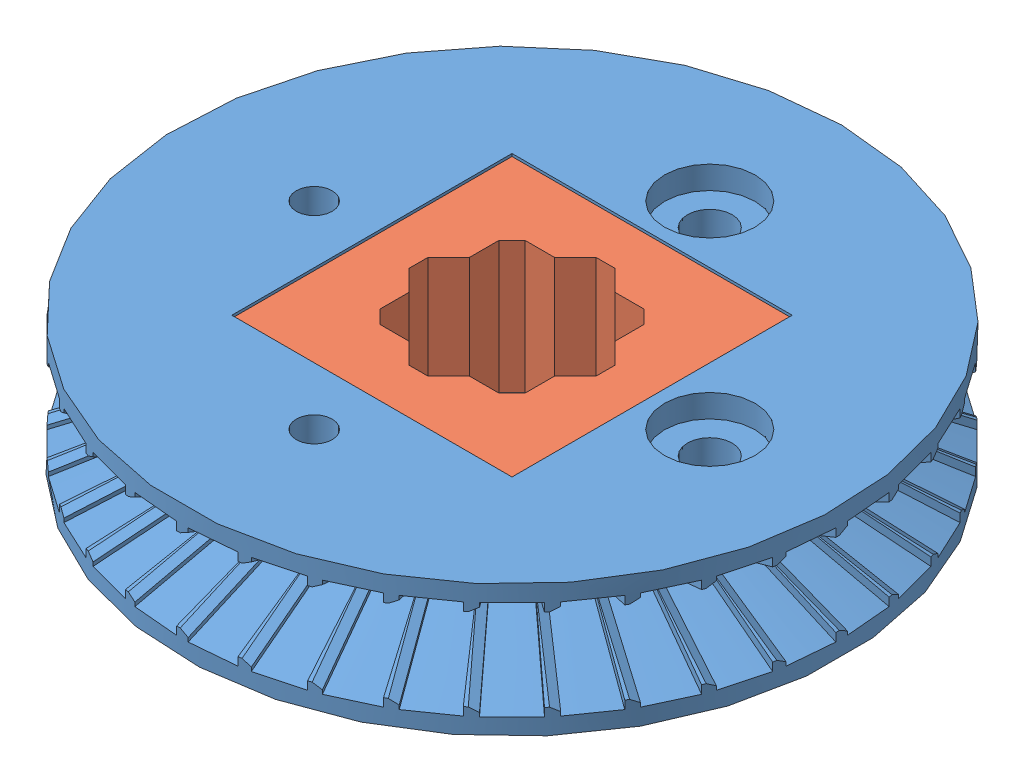
SolidWorks assembly AngledToothWinchDrum, configuration Default. Lengths in mm.
Overall size (63.5 12.7 63.5).
3 component instances, 2 part files, 5 mates.
Components (placement in the parent):
- AngledToothWinchDriver-1: AngledToothWinchDriver [Default] at origin size (63.5 6.35 63.5)
- AngledToothWinchDriver-2: AngledToothWinchDriver [Mirrored] at (0 12.7 0) x (0 0 1) z (1 0 0) size (63.5 6.35 63.5)
- MazdaMotorWinchPlug-1: MazdaMotorWinchPlug [Default] at (0.127 6.35 0.127) size (29.91 12.7 29.91)
Mates (geometry in assembly coordinates):
- Coincident1: coincident anti-aligned: plane of AngledToothWinchDriver-1 through (22.225 6.35 0) normal (0 1 0); plane of AngledToothWinchDriver-2 through (0 6.35 22.225) normal (0 -1 0)
- Concentric1: concentric anti-aligned: cylinder of AngledToothWinchDriver-2 through (19.05 12.7 0) axis (0 1 0) radius 2.1526; cylinder of AngledToothWinchDriver-1 through (19.05 0 0) axis (0 -1 0) radius 1.7272
- Concentric2: concentric anti-aligned: cylinder of AngledToothWinchDriver-1 through (0 0 -19.05) axis (0 -1 0) radius 1.7272; cylinder of AngledToothWinchDriver-2 through (0 12.7 -19.05) axis (0 1 0) radius 2.1526
- Coincident2: coincident anti-aligned: line of AngledToothWinchDriver-2 through (13.4938 12.7 13.4938) axis (-1 0 0); line of MazdaMotorWinchPlug-1 through (-13.2397 12.7 13.4938) axis (1 0 0)
- Coincident3: coincident anti-aligned: line of AngledToothWinchDriver-2 through (13.4938 12.7 -13.4938) axis (0 0 1); line of MazdaMotorWinchPlug-1 through (13.4938 12.7 13.4938) axis (0 0 -1)
